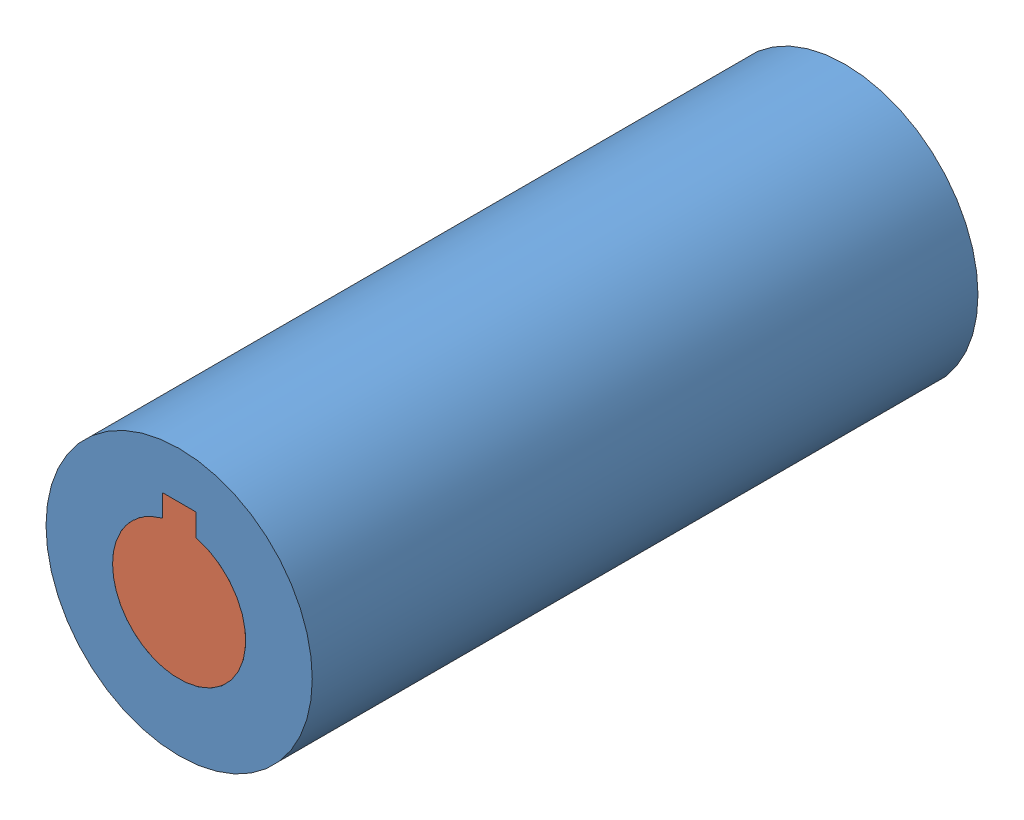
SolidWorks assembly Assem1, configuration Default. Lengths in mm.
Overall size (40 40 100).
2 component instances, 2 part files, 2 mates.
Components (placement in the parent):
- keyhole-1: keyhole [Default] at (20.3123 54.8332 83.9383) size (40 40 100)
- keyway-1: keyway [Default] at (20.3123 54.8332 83.9383) size (20 23 100)
Mates (geometry in assembly coordinates):
- Concentric3: concentric: cylinder of keyhole-1 through (20.3123 54.8332 133.9383) axis (0 0 -1) radius 10; cylinder of keyway-1 through (20.3123 54.8332 133.9383) axis (0 0 -1) radius 10
- Coincident1: coincident aligned: plane of keyhole-1 through (20.3123 54.8332 133.9383) normal (0 0 1); plane of keyway-1 through (20.3123 54.8332 133.9383) normal (0 0 1)
